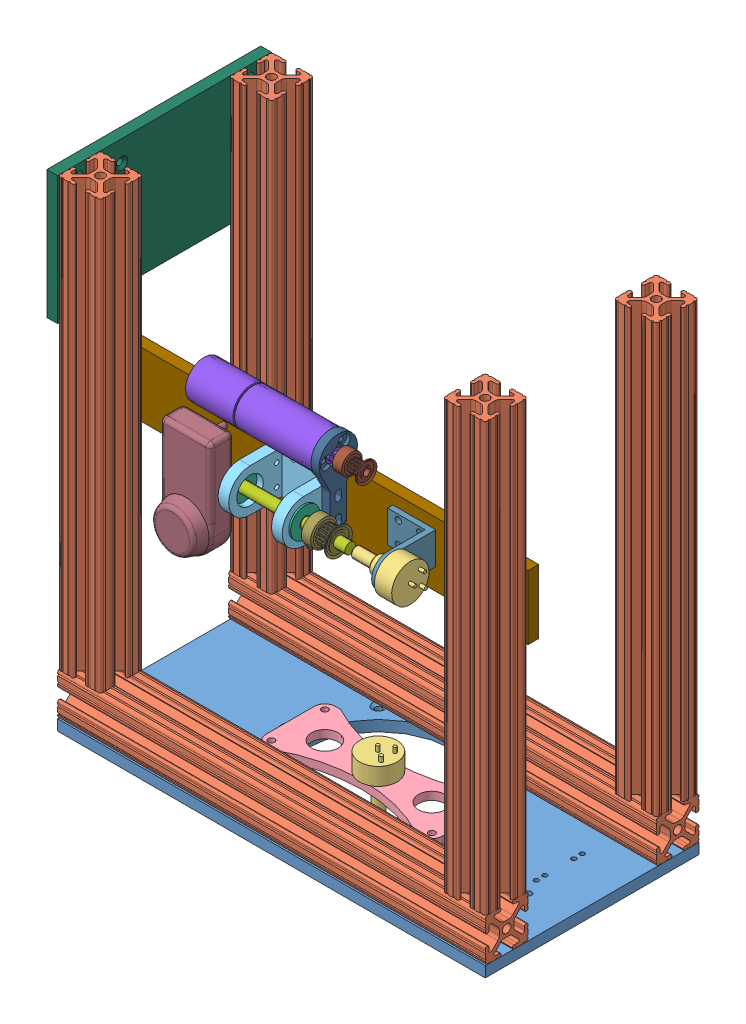
SolidWorks assembly body-frame, configuration Default. Lengths in mm.
Overall size (260.35 296.86 139.7).
23 component instances, 15 part files, 29 mates.
Components (placement in the parent):
- y01body-bottom-1: y01body-bottom [Default] at origin size (254 6.35 127)
- 80-20-10in-1: 80-20-10in [Default] at (-127 6.35 63.5) x (0 0 -1) z (1 0 0) size (25.4 25.4 254)
- 80-20-10in-2: 80-20-10in [Default] at (127 6.35 -63.5) x (0 0 1) z (-1 0 0) size (25.4 25.4 254)
- 80-20-10in-3: 80-20-10in [Default] at (-127 31.75 38.1) x (0 0 1) z (0 1 0) size (25.4 25.4 254)
- 80-20-10in-4: 80-20-10in [Default] at (-127 31.75 -38.1) x (1 0 0) z (0 1 0) size (25.4 25.4 254)
- 80-20-10in-5: 80-20-10in [Default] at (127 31.75 63.5) x (0 0 -1) z (0 1 0) size (25.4 25.4 254)
- 80-20-10in-6: 80-20-10in [Default] at (101.6 31.75 -38.1) x (1 0 0) z (0 1 0) size (25.4 25.4 254)
- bourns-6639-1: bourns-6639 [Default] at (0 21.4249 0) x (0 1 0) z (0 0 1) size (35.71 22.23 22.23)
- y13-pot-holder-1: y13-pot-holder [Default] at (0 6.35 0) size (104.77 4.76 41.27)
- NECK_YOKE_ASM-1: NECK_YOKE_ASM [Default] at (0 180.975 38.1) x (0 -1 0) z (-1 0 0) size (86.8 44.45 254)
  - n01-yoke-2: n01-yoke [Default] at origin size (25.4 38.1 38.1)
  - 000_rb-p25xp625-57155K324mcm-1: 000_rb-p25xp625-57155K324mcm [Default] at (0 25.4 -16.51) x (0 0 1) z (-0.947787 -0.318905 0) size (3.61 17.53 17.53)
  - 000_rb-p25xp625-57155K324mcm-2: 000_rb-p25xp625-57155K324mcm [Default] at (0 25.4 16.51) x (0 0 -1) z (0.870377 -0.492386 0) size (3.61 17.53 17.53)
  - n02-neck-pitch-shaft-1: n02-neck-pitch-shaft [Default] at (0 25.4 -11.8618) x (0.984383 -0.176038 0) z (0 0 1) size (6.34 6.34 69.85)
  - bourns-6639-1: bourns-6639 [Default] at (0 25.4 -82.4992) x (0 0 -1) z (0.999946 -0.010393 0) size (35.71 22.23 22.23)
  - MAXON-amax22-n-gear143991-1: MAXON-amax22-n-gear143991 [Default] at (-27.94 9.525 26.75) x (0 0 1) z (-1 0 0) size (89.5 22 22)
  - n03-neck-baseplate-to-body-1: n03-neck-baseplate-to-body [Default] at (3.175 0 0) x (0 0 -1) z (0 -1 0) size (254 38.1 6.35)
  - n04-motor-mount-1: n04-motor-mount [Default] at (-27.94 9.525 -19.05) x (-1 0 0) z (0 0 -1) size (49.53 22.86 4.76)
  - a_6d16m012df6003-3mm-bored-to-4mm-1: a_6d16m012df6003-3mm-bored-to-4mm [Default] at (-27.94 9.525 -32.3525) size (12.2 12.2 14.3)
  - a_6d16-018df2508-2: a_6d16-018df2508 [Default] at (0 25.4 -31.6681) x (0.999994 -0.003333 0) z (0 0 1) size (16.13 16.13 14.29)
  - LOGITECH_USB_CAM-1: LOGITECH_USB_CAM [Default] at (32.385 15.875 46.7995) x (0 0 -1) z (0 1 0) size (30.1 63.31 29.21)
  - n11-neck-pot-holder-2: n11-neck-pot-holder [Default] at (0 0 -59.4868) size (19.05 34.92 25.4)
- a05-plate-to-body-1: a05-plate-to-body [Default] at (-127 247.65 0) x (0 0 1) z (-1 0 0) size (127 76.2 6.35)
Mates (geometry in assembly coordinates):
- Coincident1: coincident aligned: plane of y01body-bottom-1 through (-127 6.35 -63.5) normal (0 1 0); plane of 80-20-10in-1 through (-127 6.35 63.5) normal (0 1 0)
- Coincident2: coincident aligned: plane of 80-20-10in-1 through (-127 6.35 63.5) normal (0 1 0); plane of 80-20-10in-2 through (127 6.35 -63.5) normal (0 1 0)
- Coincident3: coincident aligned: plane of 80-20-10in-1 through (127 9.5516 63.5) normal (0 0 1); plane of y01body-bottom-1 through (-127 6.35 63.5) normal (0 0 1)
- Coincident4: coincident aligned: plane of y01body-bottom-1 through (-127 6.35 -63.5) normal (0 0 -1); plane of 80-20-10in-2 through (-127 28.5484 -63.5) normal (0 0 -1)
- Coincident5: coincident aligned: plane of y01body-bottom-1 through (127 6.35 -63.5) normal (1 0 0); plane of 80-20-10in-2 through (127 7.3801 -46.3972) normal (1 0 0)
- Coincident6: coincident aligned: plane of 80-20-10in-1 through (127 7.3801 46.3972) normal (1 0 0); plane of 80-20-10in-2 through (127 7.3801 -46.3972) normal (1 0 0)
- Coincident7: coincident anti-aligned: plane of 80-20-10in-1 through (127 31.75 57.1353) normal (0 1 0); plane of 80-20-10in-5 through (125.9699 31.75 46.3972) normal (0 -1 0)
- Coincident8: coincident aligned: plane of 80-20-10in-5 through (125.9699 31.75 46.3972) normal (0 -1 0); plane of 80-20-10in-6 through (118.7028 31.75 -39.1301) normal (0 -1 0)
- Coincident9: coincident aligned: plane of 80-20-10in-3 through (-125.9699 31.75 55.2028) normal (0 -1 0); plane of 80-20-10in-5 through (125.9699 31.75 46.3972) normal (0 -1 0)
- Coincident10: coincident aligned: plane of 80-20-10in-4 through (-109.8972 31.75 -39.1301) normal (0 -1 0); plane of 80-20-10in-5 through (125.9699 31.75 46.3972) normal (0 -1 0)
- Coincident11: coincident aligned: plane of y01body-bottom-1 through (127 6.35 -63.5) normal (1 0 0); plane of 80-20-10in-5 through (127 285.75 57.1353) normal (1 0 0)
- Coincident12: coincident aligned: plane of y01body-bottom-1 through (127 6.35 -63.5) normal (1 0 0); plane of 80-20-10in-6 through (127 285.75 -41.3016) normal (1 0 0)
- Coincident13: coincident aligned: plane of y01body-bottom-1 through (-127 6.35 -63.5) normal (0 0 -1); plane of 80-20-10in-6 through (120.6353 285.75 -63.5) normal (0 0 -1)
- Coincident14: coincident aligned: plane of 80-20-10in-4 through (-120.6353 285.75 -63.5) normal (0 0 -1); plane of 80-20-10in-6 through (120.6353 285.75 -63.5) normal (0 0 -1)
- Coincident15: coincident aligned: plane of y01body-bottom-1 through (-127 6.35 -63.5) normal (-1 0 0); plane of 80-20-10in-4 through (-127 285.75 -60.2984) normal (-1 0 0)
- Coincident16: coincident aligned: plane of y01body-bottom-1 through (-127 6.35 -63.5) normal (-1 0 0); plane of 80-20-10in-3 through (-127 285.75 44.4647) normal (-1 0 0)
- Coincident17: coincident aligned: plane of y01body-bottom-1 through (-127 6.35 63.5) normal (0 0 1); plane of 80-20-10in-3 through (-123.7984 285.75 63.5) normal (0 0 1)
- Coincident18: coincident aligned: plane of y01body-bottom-1 through (-127 6.35 63.5) normal (0 0 1); plane of 80-20-10in-5 through (123.7984 285.75 63.5) normal (0 0 1)
- Concentric1: concentric aligned: cylinder of y01body-bottom-1; cylinder of y13-pot-holder-1
- Coincident19: coincident anti-aligned: plane of y01body-bottom-1 through (-127 6.35 -63.5) normal (0 1 0); plane of y13-pot-holder-1 through (-52.3875 6.35 20.6375) normal (0 -1 0)
- Concentric2: concentric aligned: cylinder of y01body-bottom-1; cylinder of y13-pot-holder-1
- Concentric3: concentric anti-aligned: cylinder of bourns-6639-1; cylinder of y13-pot-holder-1
- Coincident20: coincident anti-aligned: plane of bourns-6639-1 through (-11.1125 11.1125 0) normal (0 -1 0); plane of y13-pot-holder-1 through (-52.3875 11.1125 20.6375) normal (0 1 0)
- Coincident21: coincident anti-aligned: plane of 80-20-10in-3; plane of NECK_YOKE_ASM-1/n03-neck-baseplate-to-body-1 through (-127 196.85 38.1) normal (0 0 1)
- Coincident22: coincident aligned: plane of 80-20-10in-3; plane of NECK_YOKE_ASM-1/n03-neck-baseplate-to-body-1 through (-127 158.75 31.75) normal (-1 0 0)
- Distance1: distance = 152.4 mm anti-aligned: plane of y01body-bottom-1 through (-127 6.35 -63.5) normal (0 1 0); plane of NECK_YOKE_ASM-1/n03-neck-baseplate-to-body-1 through (-127 158.75 31.75) normal (0 -1 0)
- Coincident23: coincident anti-aligned: plane of 80-20-10in-3; plane of a05-plate-to-body-1 through (-127 209.55 -63.5) normal (1 0 0)
- Coincident24: coincident aligned: plane of 80-20-10in-4; plane of a05-plate-to-body-1 through (-133.35 285.75 -63.5) normal (0 0 -1)
- Coincident25: coincident aligned: plane of 80-20-10in-4; plane of a05-plate-to-body-1 through (-133.35 285.75 -63.5) normal (0 1 0)
